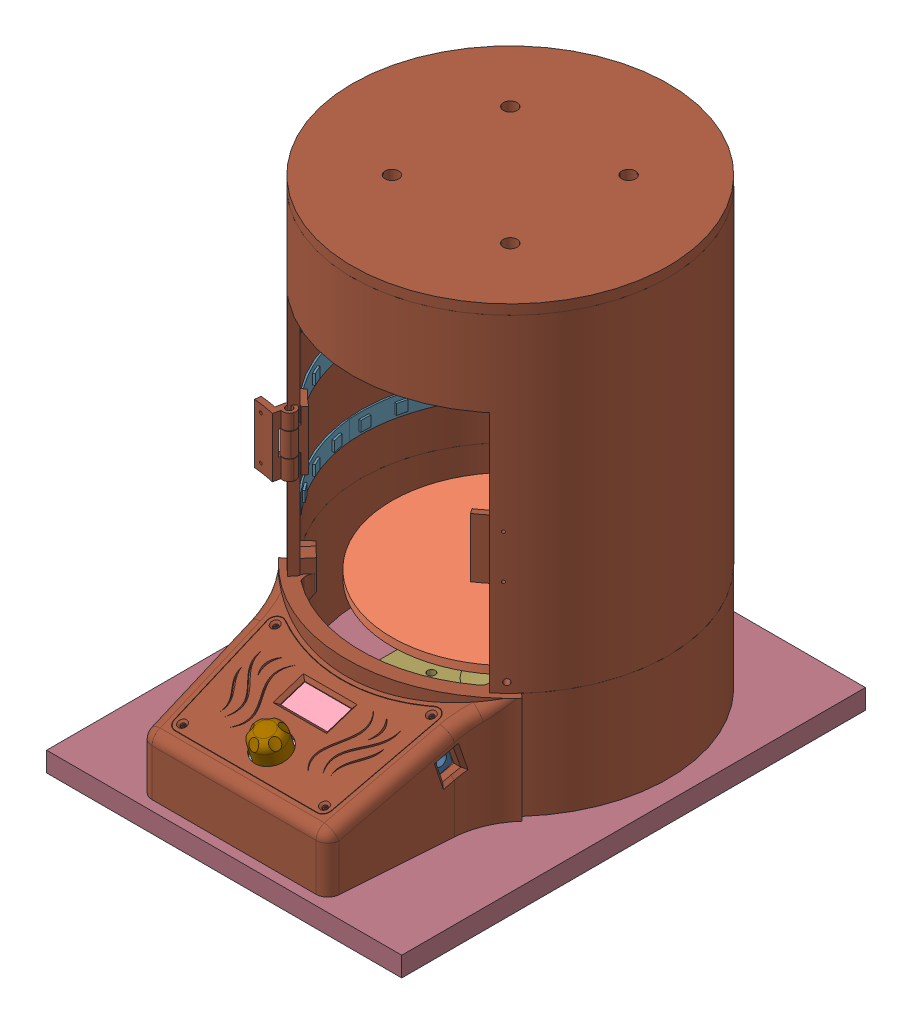
SolidWorks assembly secador uv, configuration Predeterminado. Lengths in mm.
Overall size (180 268.37 235).
62 component instances, 17 part files, 26 mates.
Components (placement in the parent):
- 28BYJ-48_v1-1: 28BYJ-48_v1 [Varsayılan] at (50.9405 35.99 0) x (0 0 1) z (-1 0 0) size (42 31.33 28)
- base-1: base [T9|9] at (0 44 0) x (0 1 0) z (0.183931 0 0.982939) size (22 120 120)
- bevel gear1-1: bevel gear1 [T9|9] at (0 44 0) x (1 0 0) z (0 0.815161 0.579234) size (7 26.31 26.31)
- ULN2003-1: ULN2003 [Predeterminado] at (0.6869 1.7264 -36.2364) size (35 11.5 32) (hidden)
- lora asemb^secador uv-2: lora asemb^secador uv [Predeterminado] at (4.0303 32.0412 88.7637) x (0 0.309017 -0.951057) z (0 0.951057 0.309017) size (67.88 82.13 41.97) (virtual)
  - esp32 lora^lora asemb_secador uv-1: esp32 lora^lora asemb_secador uv [Predeterminado] at (-5.2688 12.3128 13) x (0 -1 0) z (0 0 1) size (52 25.5 18) (virtual)
  - pcb 7 x5^lora asemb_secador uv-1: pcb 7 x5^lora asemb_secador uv [Predeterminado] x (1 0 0) z (0 -1 0) size (60 1.5 80) (virtual)
  - pin 2.54^lora asemb_secador uv-1: pin 2.54^lora asemb_secador uv [3] at (-12.1404 -2.8557 0) x (0 1 0) z (-1 0 0) size (8.5 12.1 6.3) (virtual)
  - pin 2.54^lora asemb_secador uv-2: pin 2.54^lora asemb_secador uv [2] at (-12.1404 5.6443 0) x (0 1 0) z (-1 0 0) size (5.5 12.1 6.3) (virtual)
  - pin 2.54^lora asemb_secador uv-3: pin 2.54^lora asemb_secador uv [2] at (30.0646 -12.1131 1.5) x (0 1 0) z (1 0 0) size (5.5 12.1 6.3) (virtual)
  - pin 2.54^lora asemb_secador uv-4: pin 2.54^lora asemb_secador uv [2] at (30.0646 -6.6131 1.5) x (0 1 0) z (1 0 0) size (5.5 12.1 6.3) (virtual)
  - pin 2.54^lora asemb_secador uv-5: pin 2.54^lora asemb_secador uv [2] at (30.0646 26.3967 1.5) x (0 1 0) z (1 0 0) size (5.5 12.1 6.3) (virtual)
  - to220^lora asemb_secador uv-1: to220^lora asemb_secador uv [Predeterminado] at (1.4429 -25.3578 2.5) x (0 -1 0) z (0 0 -1) size (15 10 26.75) (virtual)
  - to220^lora asemb_secador uv-2: to220^lora asemb_secador uv [Predeterminado] at (-19.0809 -28.1293 2.5) x (-1 0 0) z (0 0 -1) size (15 10 26.75) (virtual)
  - pin 5.08^lora asemb_secador uv-1: pin 5.08^lora asemb_secador uv [Predeterminado] at (30.282 -22.7639 1.5) x (0 1 0) z (1 0 0) size (10 15 7.6) (virtual)
  - rotary encoder^lora asemb_secador uv-1: rotary encoder^lora asemb_secador uv [Predeterminado] at (-27.102 3.8442 -7.4) x (0 1 0) z (1 0 0) size (19.09 40.32 31.4) (virtual)
  - 12v-1: 12v [Predeterminado] at (10.0033 -42.1277 1.5) x (0 1 0) z (1 0 0) size (14 15 9)
- tubo^secador uv-1: tubo^secador uv [Predeterminado] at (0 10 0) x (1 0 0) z (0 1 0) size (230.48 220.13 225) (virtual)
- soporte^secador uv-1: soporte^secador uv [Predeterminado] at (0 14 0) x (1 0 0) z (0 0 -1) size (82.58 33.99 50) (virtual)
- tabla^secador uv-1: tabla^secador uv [Predeterminado] at (0 10 0) x (1 0 0) z (0 -1 0) size (180 235 10) (virtual)
- zona impresión ^secador uv-1: zona impresión ^secador uv [Predeterminado] at (0 62 0) x (-0.183931 0 -0.982939) z (0 1 0) size (120 68 150) (hidden, virtual)
- tira de leds^secador uv-1: tira de leds^secador uv [Predeterminado] at origin size (161.5 146.07 157.73) (virtual)
  - 12v-1: 12v [Predeterminado] at (-9.7895 0 0) size (14 15 9) (hidden)
  - Pieza1^tira de leds_secador uv-1: Pieza1^tira de leds_secador uv [Predeterminado] at origin (hidden, virtual)
  - led 5050 5cm^tira de leds_secador uv-1: led 5050 5cm^tira de leds_secador uv [Predeterminado] at (-45 230 0) x (0 0 -1) z (-1 0 0) size (50 2 10) (virtual)
  - led 5050 5cm^tira de leds_secador uv-2: led 5050 5cm^tira de leds_secador uv [Predeterminado] at (-45 230 50) x (0 0 -1) z (-1 0 0) size (50 2 10) (virtual)
  - led 5050 5cm^tira de leds_secador uv-3: led 5050 5cm^tira de leds_secador uv [Predeterminado] at (-15 230 0) x (0 0 -1) z (-1 0 0) size (50 2 10) (virtual)
  - led 5050 5cm^tira de leds_secador uv-4: led 5050 5cm^tira de leds_secador uv [Predeterminado] at (-15 230 50) x (0 0 -1) z (-1 0 0) size (50 2 10) (virtual)
  - led 5050 5cm^tira de leds_secador uv-5: led 5050 5cm^tira de leds_secador uv [Predeterminado] at (15 230 0) x (0 0 -1) z (-1 0 0) size (50 2 10) (virtual)
  - led 5050 5cm^tira de leds_secador uv-6: led 5050 5cm^tira de leds_secador uv [Predeterminado] at (15 230 50) x (0 0 -1) z (-1 0 0) size (50 2 10) (virtual)
  - led 5050 5cm^tira de leds_secador uv-7: led 5050 5cm^tira de leds_secador uv [160mm] at (59.9944 89 52.5374) x (0.388904 0 -0.921278) z (0 1 0) size (49.61 6.28 10.16) (virtual)
  - led 5050 5cm^tira de leds_secador uv-8: led 5050 5cm^tira de leds_secador uv [160mm] at (79.609 89 4.6806) x (-0.258105 0 -0.966117) z (0 1 0) size (49.61 6.28 10.16) (virtual)
  - led 5050 5cm^tira de leds_secador uv-9: led 5050 5cm^tira de leds_secador uv [160mm] at (65.7376 89 -45.145) x (-0.796547 0 -0.604577) z (0 1 0) size (49.61 6.28 10.16) (virtual)
  - led 5050 5cm^tira de leds_secador uv-10: led 5050 5cm^tira de leds_secador uv [160mm] at (24.2149 89 -75.9812) x (-0.999937 0 0.011267) z (0 1 0) size (49.61 6.28 10.16) (virtual)
  - led 5050 5cm^tira de leds_secador uv-11: led 5050 5cm^tira de leds_secador uv [160mm] at (-27.4933 89 -74.8573) x (-0.782722 0 0.622372) z (0 1 0) size (49.61 6.28 10.16) (virtual)
  - led 5050 5cm^tira de leds_secador uv-12: led 5050 5cm^tira de leds_secador uv [160mm] at (-67.637 89 -42.2461) x (-0.23627 0 0.971688) z (0 1 0) size (49.61 6.28 10.16) (virtual)
  - led 5050 5cm^tira de leds_secador uv-13: led 5050 5cm^tira de leds_secador uv [160mm] at (-79.3305 89 8.1351) x (0.409565 0 0.912281) z (0 1 0) size (49.61 6.28 10.16) (virtual)
  - led 5050 5cm^tira de leds_secador uv-14: led 5050 5cm^tira de leds_secador uv [160mm] at (59.9944 129 52.5374) x (0.388904 0 -0.921278) z (0 1 0) size (49.61 6.28 10.16) (virtual)
  - led 5050 5cm^tira de leds_secador uv-15: led 5050 5cm^tira de leds_secador uv [160mm] at (59.9944 169 52.5374) x (0.388904 0 -0.921278) z (0 1 0) size (49.61 6.28 10.16) (virtual)
  - led 5050 5cm^tira de leds_secador uv-16: led 5050 5cm^tira de leds_secador uv [160mm] at (79.609 129 4.6806) x (-0.258105 0 -0.966117) z (0 1 0) size (49.61 6.28 10.16) (virtual)
  - led 5050 5cm^tira de leds_secador uv-17: led 5050 5cm^tira de leds_secador uv [160mm] at (79.609 169 4.6806) x (-0.258105 0 -0.966117) z (0 1 0) size (49.61 6.28 10.16) (virtual)
  - led 5050 5cm^tira de leds_secador uv-18: led 5050 5cm^tira de leds_secador uv [160mm] at (65.7376 129 -45.145) x (-0.796547 0 -0.604577) z (0 1 0) size (49.61 6.28 10.16) (virtual)
  - led 5050 5cm^tira de leds_secador uv-19: led 5050 5cm^tira de leds_secador uv [160mm] at (65.7376 169 -45.145) x (-0.796547 0 -0.604577) z (0 1 0) size (49.61 6.28 10.16) (virtual)
  - led 5050 5cm^tira de leds_secador uv-20: led 5050 5cm^tira de leds_secador uv [160mm] at (24.2149 129 -75.9812) x (-0.999937 0 0.011267) z (0 1 0) size (49.61 6.28 10.16) (virtual)
  - led 5050 5cm^tira de leds_secador uv-21: led 5050 5cm^tira de leds_secador uv [160mm] at (24.2149 169 -75.9812) x (-0.999937 0 0.011267) z (0 1 0) size (49.61 6.28 10.16) (virtual)
  - led 5050 5cm^tira de leds_secador uv-22: led 5050 5cm^tira de leds_secador uv [160mm] at (-27.4933 129 -74.8573) x (-0.782722 0 0.622372) z (0 1 0) size (49.61 6.28 10.16) (virtual)
  - led 5050 5cm^tira de leds_secador uv-23: led 5050 5cm^tira de leds_secador uv [160mm] at (-27.4933 169 -74.8573) x (-0.782722 0 0.622372) z (0 1 0) size (49.61 6.28 10.16) (virtual)
  - led 5050 5cm^tira de leds_secador uv-24: led 5050 5cm^tira de leds_secador uv [160mm] at (-67.637 129 -42.2461) x (-0.23627 0 0.971688) z (0 1 0) size (49.61 6.28 10.16) (virtual)
  - led 5050 5cm^tira de leds_secador uv-25: led 5050 5cm^tira de leds_secador uv [160mm] at (-67.637 169 -42.2461) x (-0.23627 0 0.971688) z (0 1 0) size (49.61 6.28 10.16) (virtual)
  - led 5050 5cm^tira de leds_secador uv-26: led 5050 5cm^tira de leds_secador uv [160mm] at (-79.3305 129 8.1351) x (0.409565 0 0.912281) z (0 1 0) size (49.61 6.28 10.16) (virtual)
  - led 5050 5cm^tira de leds_secador uv-27: led 5050 5cm^tira de leds_secador uv [160mm] at (-79.3305 169 8.1351) x (0.409565 0 0.912281) z (0 1 0) size (49.61 6.28 10.16) (virtual)
  - led 5050 5cm^tira de leds_secador uv-28: led 5050 5cm^tira de leds_secador uv [160mm] at (38.3425 205 69.9243) x (-0.983525 0 0.18077) z (0 -1 0) size (49.61 6.28 10.16) (virtual)
  - led 5050 5cm^tira de leds_secador uv-29: led 5050 5cm^tira de leds_secador uv [160mm] at (-12.621 205 78.7418) x (-0.887579 0 -0.460655) z (0 -1 0) size (49.61 6.28 10.16) (virtual)
  - led 5050 5cm^tira de leds_secador uv-30: led 5050 5cm^tira de leds_secador uv [160mm] at (-58.2758 205 54.438) x (-0.41829 0 -0.908314) z (0 -1 0) size (49.61 6.28 10.16) (virtual)
  - led 5050 5cm^tira de leds_secador uv-31: led 5050 5cm^tira de leds_secador uv [160mm] at (-79.4179 205 7.2359) x (0.226946 0 -0.973907) z (0 -1 0) size (49.61 6.28 10.16) (virtual)
  - led 5050 5cm^tira de leds_secador uv-32: led 5050 5cm^tira de leds_secador uv [160mm] at (-67.1544 205 -43.0099) x (0.776721 0 -0.629845) z (0 -1 0) size (49.61 6.28 10.16) (virtual)
  - led 5050 5cm^tira de leds_secador uv-33: led 5050 5cm^tira de leds_secador uv [160mm] at (-26.6436 205 -75.1644) x (0.999783 0 -0.02085) z (0 -1 0) size (49.61 6.28 10.16) (virtual)
  - led 5050 5cm^tira de leds_secador uv-34: led 5050 5cm^tira de leds_secador uv [160mm] at (25.0743 205 -75.7023) x (0.802305 0 0.596915) z (0 -1 0) size (49.61 6.28 10.16) (virtual)
  - led 5050 5cm^tira de leds_secador uv-35: led 5050 5cm^tira de leds_secador uv [160mm] at (66.2452 205 -44.3975) x (0.267352 0 0.963599) z (0 -1 0) size (49.61 6.28 10.16) (virtual)
  - led 5050 5cm^tira de leds_secador uv-36: led 5050 5cm^tira de leds_secador uv [160mm] at (79.5512 205 5.5823) x (-0.380057 0 0.924963) z (0 -1 0) size (49.61 6.28 10.16) (virtual)
  - led 5050 5cm^tira de leds_secador uv-37: led 5050 5cm^tira de leds_secador uv [Predeterminado] at (45 230 0) x (0 0 -1) z (-1 0 0) size (50 2 10) (virtual)
  - led 5050 5cm^tira de leds_secador uv-38: led 5050 5cm^tira de leds_secador uv [Predeterminado] at (45 230 50) x (0 0 -1) z (-1 0 0) size (50 2 10) (virtual)
Mates (geometry in assembly coordinates):
- Coincidente4: coincident: line of assembly; line of base-1 through (44.5497 0 44) axis (0 0 1); line of assembly
- Coincidente5: coincident: point of assembly; point of base-1; point of assembly
- Coincidente6: coincident: point of assembly; point of bevel gear1-1; point of assembly
- Concéntrica3: concentric: cylinder of assembly; cylinder of assembly; cylinder of 28BYJ-48_v1-1 through (32.5905 44 0) axis (1 0 0) radius 2.48; cylinder of bevel gear1-1 through (38.6905 44 0) axis (-1 0 0) radius 2.65
- Paralelo1: parallel: plane of assembly through (0 0 0) normal (0 1 0); plane of 28BYJ-48_v1-1 through (78.0173 18.655 -8.1889) normal (0 -1 0); plane of assembly
- Coincidente20: coincident: plane of assembly through (0 0 0) normal (0 0 1); plane of 28BYJ-48_v1-1 through (50.9405 35.99 0) normal (0 0 1); plane of assembly
- Distancia1: distance = 2 mm: plane of assembly; plane of assembly; plane of lora asemb^secador uv-2/esp32 lora^lora asemb_secador uv-1 through (-8.2824 48.9587 99.8005) normal (0 0.951057 0.309017); plane of tubo^secador uv-1 through (0 81.2624 6.8521) normal (0 0.951057 0.309017)
- Paralelo4: parallel: plane of assembly through (0 0 0) normal (0 1 0); plane of ULN2003-1 through (0.6869 1.7264 -36.2364) normal (0 -1 0); plane of assembly
- Paralelo5: parallel: plane of assembly through (0 0 0) normal (0 0 1); plane of ULN2003-1 through (0.6869 1.7264 -36.2364) normal (0 0 1); plane of assembly
- Coincidente25: coincident: plane of assembly; plane of assembly; plane of 28BYJ-48_v1-1 through (38.6905 34.3225 0) normal (-1 0 0); plane of bevel gear1-1 through (38.6905 44 0) normal (1 0 0)
- Concéntrica5: concentric: cylinder of assembly; cylinder of assembly; cylinder of base-1 through (0 44 0) axis (0 -1 0) radius 10; cylinder of soporte^secador uv-1 through (0 14 0) axis (0 1 0) radius 10
- Concéntrica6: concentric: cylinder of assembly; cylinder of assembly; cylinder of tubo^secador uv-1 through (0 230 0) axis (0 -1 0) radius 80.1; cylinder of soporte^secador uv-1 through (0 14 0) axis (0 1 0) radius 10
- Coincidente35: coincident: plane of assembly; plane of assembly; plane of base-1 through (-11.0359 62 -58.9763) normal (0 1 0); plane of zona impresión ^secador uv-1 through (0 62 0) normal (0 -1 0)
- Coincidente36: coincident: plane of assembly; plane of assembly; plane of base-1 through (0 44 0) normal (-0.982939 0 0.183931); plane of zona impresión ^secador uv-1 through (0 62 0) normal (-0.982939 0 0.183931)
- Coincidente37: coincident: plane of assembly; plane of assembly; plane of base-1 through (0 44 0) normal (0.183931 0 0.982939); plane of zona impresión ^secador uv-1 through (0 62 0) normal (-0.183931 0 -0.982939)
- Paralelo7: parallel: plane of assembly through (0 0 0) normal (1 0 0); plane of lora asemb^secador uv-2 through (4.0303 32.0412 88.7637) normal (-1 0 0); plane of assembly
- Coincidente38: coincident: plane of assembly through (0 0 0) normal (1 0 0); plane of lora asemb^secador uv-2/esp32 lora^lora asemb_secador uv-1 through (0 42.7768 97.7919) normal (1 0 0); plane of assembly
- Coincidente39: coincident: plane of assembly; plane of assembly; plane of soporte^secador uv-1 through (0 10 0) normal (0 -1 0); plane of tabla^secador uv-1 through (0 10 0) normal (0 1 0)
- Coincidente40: coincident: plane of assembly through (0 0 0) normal (0 1 0); plane of tabla^secador uv-1 through (0 0 0) normal (0 -1 0); plane of assembly
- Coincidente41: coincident: plane of assembly through (0 0 0) normal (1 0 0); plane of tabla^secador uv-1 through (0 10 0) normal (1 0 0); plane of assembly
- Coincidente42: coincident: plane of assembly; plane of assembly; plane of tubo^secador uv-1 through (0 10 0) normal (0 -1 0); plane of tabla^secador uv-1 through (0 10 0) normal (0 1 0)
- Coincidente43: coincident: plane of assembly through (0 0 0) normal (0 0 1); plane of tabla^secador uv-1 through (0 10 0) normal (0 0 1); plane of assembly
- Coincidente44: coincident: plane of assembly through (0 0 0) normal (0 0 1); plane of soporte^secador uv-1 through (0 14 0) normal (0 0 -1); plane of assembly
- Coincidente45: coincident: plane of tira de leds^secador uv-1/Pieza1^tira de leds_secador uv-1 through (0 0 0) normal (0 0 1); plane of assembly through (0 0 0) normal (0 0 1)
- Coincidente46: coincident: plane of tira de leds^secador uv-1/Pieza1^tira de leds_secador uv-1 through (0 0 0) normal (0 1 0); plane of assembly through (0 0 0) normal (0 1 0)
- Coincidente47: coincident: plane of tira de leds^secador uv-1/Pieza1^tira de leds_secador uv-1 through (0 0 0) normal (1 0 0); plane of assembly through (0 0 0) normal (1 0 0)
